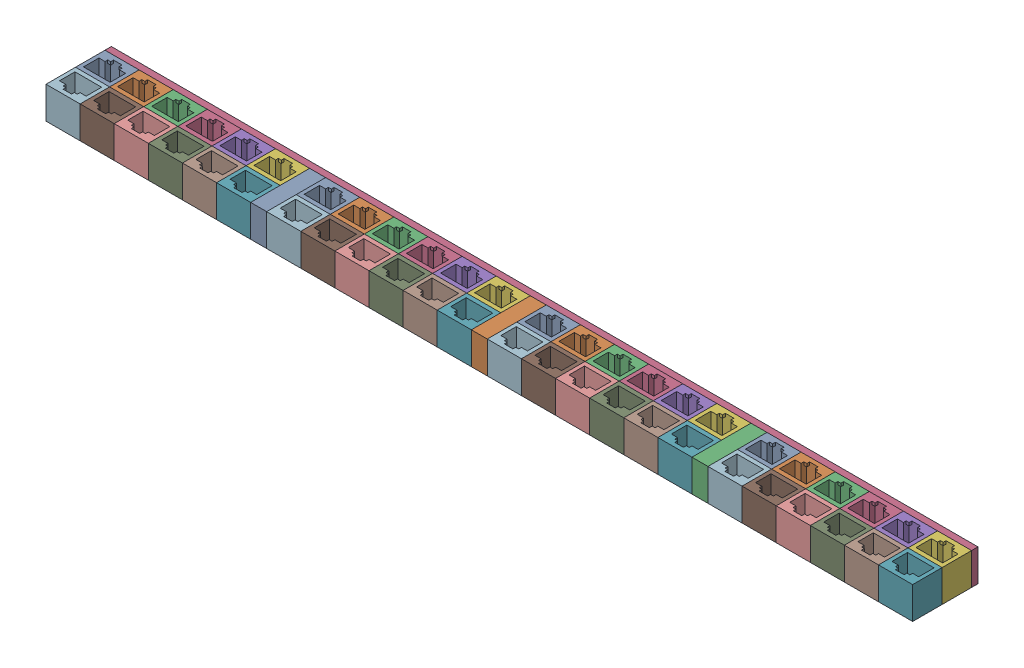
SolidWorks assembly 48-port 12-group block, configuration Default. Lengths in mm.
Overall size (406.5 15 30.66).
64 component instances, 3 part files, 22 mates.
Components (placement in the parent):
- 12-port block-1: 12-port block [Default] at (-110.7304 20.9152 88.4758) size (96 15 27.66)
  - 6-port block-1: 6-port block [Default] at (18.7671 16.9181 15.9423) size (96 15 13.83)
    - RJ45 dummy jack trimmed-1: RJ45 dummy jack trimmed [Default] at (-42.6786 6.807 34.1283) size (16 15 13.83)
    - RJ45 dummy jack trimmed-2: RJ45 dummy jack trimmed [Default] at (-26.6786 6.807 34.1283) size (16 15 13.83)
    - RJ45 dummy jack trimmed-3: RJ45 dummy jack trimmed [Default] at (-10.6786 6.807 34.1283) size (16 15 13.83)
    - RJ45 dummy jack trimmed-4: RJ45 dummy jack trimmed [Default] at (5.3214 6.807 34.1283) size (16 15 13.83)
    - RJ45 dummy jack trimmed-5: RJ45 dummy jack trimmed [Default] at (21.3214 6.807 34.1283) size (16 15 13.83)
    - RJ45 dummy jack trimmed-6: RJ45 dummy jack trimmed [Default] at (37.3214 6.807 34.1283) size (16 15 13.83)
  - 6-port block-2: 6-port block [Default] at (25.9098 16.9181 88.1988) x (-1 0 0) z (0 0 -1) size (96 15 13.83)
    - RJ45 dummy jack trimmed-1: RJ45 dummy jack trimmed [Default] at (-42.6786 6.807 34.1283) size (16 15 13.83)
    - RJ45 dummy jack trimmed-2: RJ45 dummy jack trimmed [Default] at (-26.6786 6.807 34.1283) size (16 15 13.83)
    - RJ45 dummy jack trimmed-3: RJ45 dummy jack trimmed [Default] at (-10.6786 6.807 34.1283) size (16 15 13.83)
    - RJ45 dummy jack trimmed-4: RJ45 dummy jack trimmed [Default] at (5.3214 6.807 34.1283) size (16 15 13.83)
    - RJ45 dummy jack trimmed-5: RJ45 dummy jack trimmed [Default] at (21.3214 6.807 34.1283) size (16 15 13.83)
    - RJ45 dummy jack trimmed-6: RJ45 dummy jack trimmed [Default] at (37.3214 6.807 34.1283) size (16 15 13.83)
- 12-port block-2: 12-port block [Default] at (-7.2304 20.9152 88.4758) size (96 15 27.66)
  - 6-port block-1: 6-port block [Default] at (18.7671 16.9181 15.9423) size (96 15 13.83)
    - RJ45 dummy jack trimmed-1: RJ45 dummy jack trimmed [Default] at (-42.6786 6.807 34.1283) size (16 15 13.83)
    - RJ45 dummy jack trimmed-2: RJ45 dummy jack trimmed [Default] at (-26.6786 6.807 34.1283) size (16 15 13.83)
    - RJ45 dummy jack trimmed-3: RJ45 dummy jack trimmed [Default] at (-10.6786 6.807 34.1283) size (16 15 13.83)
    - RJ45 dummy jack trimmed-4: RJ45 dummy jack trimmed [Default] at (5.3214 6.807 34.1283) size (16 15 13.83)
    - RJ45 dummy jack trimmed-5: RJ45 dummy jack trimmed [Default] at (21.3214 6.807 34.1283) size (16 15 13.83)
    - RJ45 dummy jack trimmed-6: RJ45 dummy jack trimmed [Default] at (37.3214 6.807 34.1283) size (16 15 13.83)
  - 6-port block-2: 6-port block [Default] at (25.9098 16.9181 88.1988) x (-1 0 0) z (0 0 -1) size (96 15 13.83)
    - RJ45 dummy jack trimmed-1: RJ45 dummy jack trimmed [Default] at (-42.6786 6.807 34.1283) size (16 15 13.83)
    - RJ45 dummy jack trimmed-2: RJ45 dummy jack trimmed [Default] at (-26.6786 6.807 34.1283) size (16 15 13.83)
    - RJ45 dummy jack trimmed-3: RJ45 dummy jack trimmed [Default] at (-10.6786 6.807 34.1283) size (16 15 13.83)
    - RJ45 dummy jack trimmed-4: RJ45 dummy jack trimmed [Default] at (5.3214 6.807 34.1283) size (16 15 13.83)
    - RJ45 dummy jack trimmed-5: RJ45 dummy jack trimmed [Default] at (21.3214 6.807 34.1283) size (16 15 13.83)
    - RJ45 dummy jack trimmed-6: RJ45 dummy jack trimmed [Default] at (37.3214 6.807 34.1283) size (16 15 13.83)
- 12-port block-3: 12-port block [Default] at (96.2696 20.9152 88.4758) size (96 15 27.66)
  - 6-port block-1: 6-port block [Default] at (18.7671 16.9181 15.9423) size (96 15 13.83)
    - RJ45 dummy jack trimmed-1: RJ45 dummy jack trimmed [Default] at (-42.6786 6.807 34.1283) size (16 15 13.83)
    - RJ45 dummy jack trimmed-2: RJ45 dummy jack trimmed [Default] at (-26.6786 6.807 34.1283) size (16 15 13.83)
    - RJ45 dummy jack trimmed-3: RJ45 dummy jack trimmed [Default] at (-10.6786 6.807 34.1283) size (16 15 13.83)
    - RJ45 dummy jack trimmed-4: RJ45 dummy jack trimmed [Default] at (5.3214 6.807 34.1283) size (16 15 13.83)
    - RJ45 dummy jack trimmed-5: RJ45 dummy jack trimmed [Default] at (21.3214 6.807 34.1283) size (16 15 13.83)
    - RJ45 dummy jack trimmed-6: RJ45 dummy jack trimmed [Default] at (37.3214 6.807 34.1283) size (16 15 13.83)
  - 6-port block-2: 6-port block [Default] at (25.9098 16.9181 88.1988) x (-1 0 0) z (0 0 -1) size (96 15 13.83)
    - RJ45 dummy jack trimmed-1: RJ45 dummy jack trimmed [Default] at (-42.6786 6.807 34.1283) size (16 15 13.83)
    - RJ45 dummy jack trimmed-2: RJ45 dummy jack trimmed [Default] at (-26.6786 6.807 34.1283) size (16 15 13.83)
    - RJ45 dummy jack trimmed-3: RJ45 dummy jack trimmed [Default] at (-10.6786 6.807 34.1283) size (16 15 13.83)
    - RJ45 dummy jack trimmed-4: RJ45 dummy jack trimmed [Default] at (5.3214 6.807 34.1283) size (16 15 13.83)
    - RJ45 dummy jack trimmed-5: RJ45 dummy jack trimmed [Default] at (21.3214 6.807 34.1283) size (16 15 13.83)
    - RJ45 dummy jack trimmed-6: RJ45 dummy jack trimmed [Default] at (37.3214 6.807 34.1283) size (16 15 13.83)
- 12-port block-4: 12-port block [Default] at (199.7696 20.9152 88.4758) size (96 15 27.66)
  - 6-port block-1: 6-port block [Default] at (18.7671 16.9181 15.9423) size (96 15 13.83)
    - RJ45 dummy jack trimmed-1: RJ45 dummy jack trimmed [Default] at (-42.6786 6.807 34.1283) size (16 15 13.83)
    - RJ45 dummy jack trimmed-2: RJ45 dummy jack trimmed [Default] at (-26.6786 6.807 34.1283) size (16 15 13.83)
    - RJ45 dummy jack trimmed-3: RJ45 dummy jack trimmed [Default] at (-10.6786 6.807 34.1283) size (16 15 13.83)
    - RJ45 dummy jack trimmed-4: RJ45 dummy jack trimmed [Default] at (5.3214 6.807 34.1283) size (16 15 13.83)
    - RJ45 dummy jack trimmed-5: RJ45 dummy jack trimmed [Default] at (21.3214 6.807 34.1283) size (16 15 13.83)
    - RJ45 dummy jack trimmed-6: RJ45 dummy jack trimmed [Default] at (37.3214 6.807 34.1283) size (16 15 13.83)
  - 6-port block-2: 6-port block [Default] at (25.9098 16.9181 88.1988) x (-1 0 0) z (0 0 -1) size (96 15 13.83)
    - RJ45 dummy jack trimmed-1: RJ45 dummy jack trimmed [Default] at (-42.6786 6.807 34.1283) size (16 15 13.83)
    - RJ45 dummy jack trimmed-2: RJ45 dummy jack trimmed [Default] at (-26.6786 6.807 34.1283) size (16 15 13.83)
    - RJ45 dummy jack trimmed-3: RJ45 dummy jack trimmed [Default] at (-10.6786 6.807 34.1283) size (16 15 13.83)
    - RJ45 dummy jack trimmed-4: RJ45 dummy jack trimmed [Default] at (5.3214 6.807 34.1283) size (16 15 13.83)
    - RJ45 dummy jack trimmed-5: RJ45 dummy jack trimmed [Default] at (21.3214 6.807 34.1283) size (16 15 13.83)
    - RJ45 dummy jack trimmed-6: RJ45 dummy jack trimmed [Default] at (37.3214 6.807 34.1283) size (16 15 13.83)
- RJ45 spacer block-1: RJ45 spacer block [Default] at (-40.3919 44.6403 154.3763) size (7.5 15 27.66)
- RJ45 spacer block-2: RJ45 spacer block [Default] at (63.1081 44.6403 154.3763) size (7.5 15 27.66)
- RJ45 spacer block-3: RJ45 spacer block [Default] at (166.6081 44.6403 154.3763) size (7.5 15 27.66)
- RJ45 48-port 12-group top plate-1: RJ45 48-port 12-group top plate [Default] at (-136.3919 69.6403 126.7163) x (1 0 0) z (0 1 0) size (406.5 3 15)
Mates (geometry in assembly coordinates):
- Coincident1: coincident anti-aligned: plane of 12-port block-1/6-port block-1/RJ45 dummy jack trimmed-6 through (-40.3919 69.6403 126.7163) normal (1 0 0); plane of RJ45 spacer block-1 through (-40.3919 69.6403 154.3763) normal (-1 0 0)
- Coincident2: coincident: point of 12-port block-1/6-port block-1/RJ45 dummy jack trimmed-6; unknown of RJ45 spacer block-1
- Coincident3: coincident: unknown of 12-port block-1/6-port block-1/RJ45 dummy jack trimmed-6; unknown of RJ45 spacer block-1
- Coincident4: coincident anti-aligned: plane of 12-port block-2/6-port block-1/RJ45 dummy jack trimmed-1 through (-32.8919 69.6403 126.7163) normal (-1 0 0); plane of RJ45 spacer block-1 through (-32.8919 69.6403 154.3763) normal (1 0 0)
- Coincident5: coincident: unknown of 12-port block-2/6-port block-1/RJ45 dummy jack trimmed-1; unknown of RJ45 spacer block-1
- Coincident6: coincident: line of 12-port block-2/6-port block-2/RJ45 dummy jack trimmed-6 through (-32.8919 69.6403 140.5463) axis (0 0 1); unknown of RJ45 spacer block-1
- Coincident7: coincident anti-aligned: plane of 12-port block-2/6-port block-1/RJ45 dummy jack trimmed-6 through (63.1081 69.6403 126.7163) normal (1 0 0); plane of RJ45 spacer block-2 through (63.1081 69.6403 154.3763) normal (-1 0 0)
- Coincident8: coincident: unknown of 12-port block-2/6-port block-1/RJ45 dummy jack trimmed-6; unknown of RJ45 spacer block-2
- Coincident10: coincident: unknown of 12-port block-2/6-port block-1/RJ45 dummy jack trimmed-6; unknown of RJ45 spacer block-2
- Coincident11: coincident: unknown of 12-port block-2/6-port block-2/RJ45 dummy jack trimmed-1; unknown of RJ45 spacer block-2
- Coincident12: coincident anti-aligned: plane of 12-port block-3/6-port block-1/RJ45 dummy jack trimmed-1 through (70.6081 69.6403 126.7163) normal (-1 0 0); plane of RJ45 spacer block-2 through (70.6081 69.6403 154.3763) normal (1 0 0)
- Coincident13: coincident: unknown of 12-port block-3/6-port block-1/RJ45 dummy jack trimmed-1; unknown of RJ45 spacer block-2
- Coincident14: coincident: unknown of 12-port block-3/6-port block-1/RJ45 dummy jack trimmed-1; unknown of RJ45 spacer block-2
- Coincident15: coincident anti-aligned: plane of 12-port block-3/6-port block-1/RJ45 dummy jack trimmed-6 through (166.6081 69.6403 126.7163) normal (1 0 0); plane of RJ45 spacer block-3 through (166.6081 69.6403 154.3763) normal (-1 0 0)
- Coincident16: coincident: unknown of 12-port block-3/6-port block-1/RJ45 dummy jack trimmed-6; unknown of RJ45 spacer block-3
- Coincident17: coincident: line of 12-port block-3/6-port block-2/RJ45 dummy jack trimmed-1 through (166.6081 69.6403 154.3763) axis (0 0 -1); unknown of RJ45 spacer block-3
- Coincident18: coincident anti-aligned: plane of 12-port block-4/6-port block-1/RJ45 dummy jack trimmed-1 through (174.1081 69.6403 126.7163) normal (-1 0 0); plane of RJ45 spacer block-3 through (174.1081 69.6403 154.3763) normal (1 0 0)
- Coincident19: coincident: unknown of 12-port block-4/6-port block-2/RJ45 dummy jack trimmed-6; unknown of RJ45 spacer block-3
- Coincident20: coincident: unknown of 12-port block-4/6-port block-1/RJ45 dummy jack trimmed-1; unknown of RJ45 spacer block-3
- Coincident21: coincident anti-aligned: plane of 12-port block-4/6-port block-1/RJ45 dummy jack trimmed-6 through (254.1081 69.6403 126.7163) normal (0 0 -1); plane of RJ45 48-port 12-group top plate-1 through (-136.3919 69.6403 126.7163) normal (0 0 1)
- Coincident22: coincident: unknown of 12-port block-4/6-port block-1/RJ45 dummy jack trimmed-6; unknown of RJ45 48-port 12-group top plate-1
- Coincident23: coincident: unknown of RJ45 spacer block-2; unknown of RJ45 48-port 12-group top plate-1
